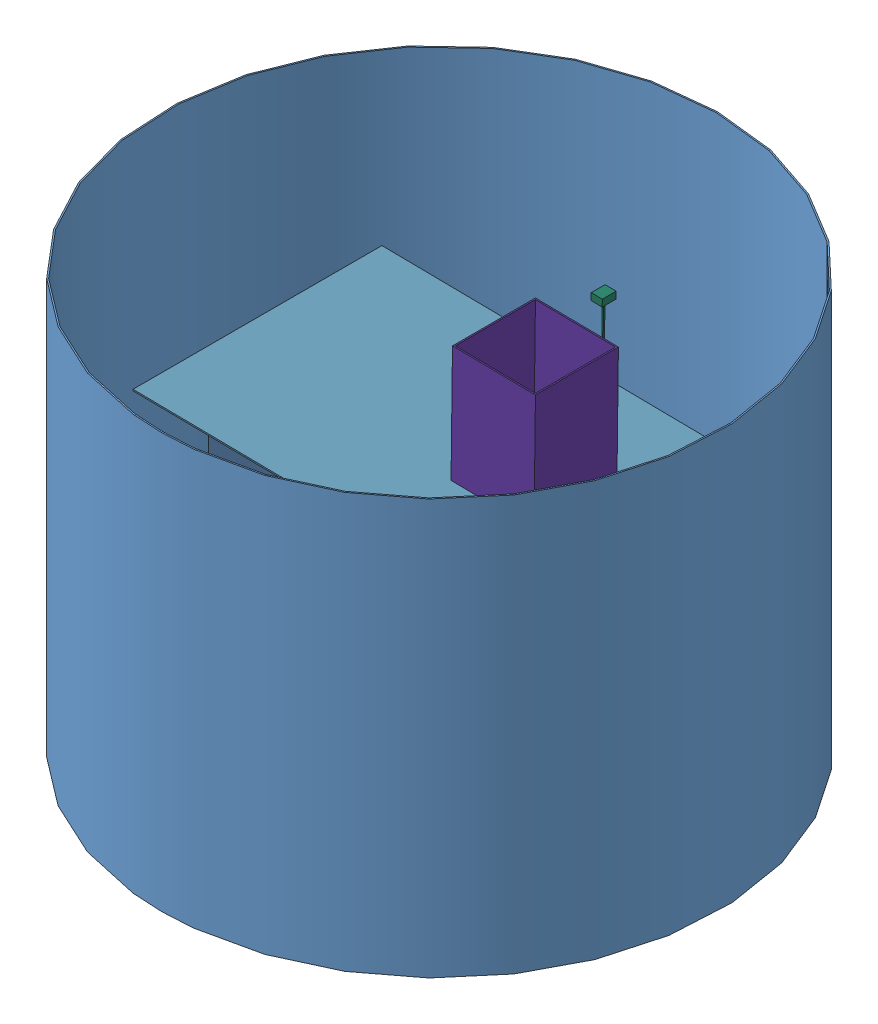
SolidWorks assembly Rover Lander assem, configuration Default. Lengths in mm.
Overall size (4020 3109.73 4020).
98 component instances, 37 part files, 5 mates.
Components (placement in the parent):
- lander_base_assem-1: lander_base_assem [Default] at (-53.6849 8.2156 22.7472) size (3202.83 1516.81 3190.9)
  - Lander base-1: Lander base [Default] at (714.6592 -461.0878 -63.8597) size (2500 70 1780)
  - leg_aluminum_rev-1: leg_aluminum_rev [Default] at (365.8635 -910.6524 482.3383) x (0 0.000985 1) z (-1 0 0) size (725.04 964.3 300)
    - base_leg-1: base_leg [Default] at (9.2435 -7.9699 0.537) size (300 140 300)
    - Main_leg-1: Main_leg [Default] at (-240.1972 521.872 0.537) x (0 0 -1) z (0.869495 0.493942 0) size (120 996.55 163.86)
    - Support_leg-1: Support_leg [Default] at (-74.206 133.9648 -89.463) x (0 0 -1) z (0.548366 0.836238 0) size (45 600 45)
    - leg_pin-1: leg_pin [Default] at (9.2435 82.777 -99.463) x (0 0 1) z (-0.667547 0.744568 0) size (200 20 20)
    - Support_leg-2: Support_leg [Default] at (-74.206 133.9648 90.537) x (0 0 -1) z (0.548366 0.836238 0) size (45 600 45)
    - leg_support_pin-1: leg_support_pin [Default] at (-40.7565 112.0301 -76.463) x (0 0 -1) z (1 0 0) size (26 10 10)
    - leg_support_pin-2: leg_support_pin [Default] at (-40.7565 112.0301 103.537) x (0 0 -1) z (1 0 0) size (26 10 10)
    - leg_joiner-1: leg_joiner [Default] at (-525.7944 410.0826 0.537) x (1 -0.000985 0) z (0 0 1) size (60 470.09 206)
    - leg_joiner_pin-1: leg_joiner_pin [Default] at (-525.3511 860.1724 -19.463) size (20 20 40)
  - leg_aluminum_rev-2: leg_aluminum_rev [Default] at (364.7896 -910.6524 -2390.0576) x (0 0.000985 -1) z (1 0 0) size (725.04 964.3 300)
    - base_leg-1: base_leg [Default] at (9.2435 -7.9699 0.537) size (300 140 300)
    - Main_leg-1: Main_leg [Default] at (-240.1972 521.872 0.537) x (0 0 -1) z (0.869495 0.493942 0) size (120 996.55 163.86)
    - Support_leg-1: Support_leg [Default] at (-74.206 133.9648 -89.463) x (0 0 -1) z (0.548366 0.836238 0) size (45 600 45)
    - leg_pin-1: leg_pin [Default] at (9.2435 82.777 -99.463) x (0 0 1) z (-0.667547 0.744568 0) size (200 20 20)
    - Support_leg-2: Support_leg [Default] at (-74.206 133.9648 90.537) x (0 0 -1) z (0.548366 0.836238 0) size (45 600 45)
    - leg_support_pin-1: leg_support_pin [Default] at (-40.7565 112.0301 -76.463) x (0 0 -1) z (1 0 0) size (26 10 10)
    - leg_support_pin-2: leg_support_pin [Default] at (-40.7565 112.0301 103.537) x (0 0 -1) z (1 0 0) size (26 10 10)
    - leg_joiner-1: leg_joiner [Default] at (-525.7944 410.0826 0.537) x (1 -0.000985 0) z (0 0 1) size (60 470.09 206)
    - leg_joiner_pin-1: leg_joiner_pin [Default] at (-525.3511 860.1724 -19.463) size (20 20 40)
  - leg_aluminum_rev-3: leg_aluminum_rev [Default] at (-1436.5452 -910.6524 -2390.0576) x (0 0.000985 -1) z (1 0 0) size (725.04 964.3 300)
    - base_leg-1: base_leg [Default] at (9.2435 -7.9699 0.537) size (300 140 300)
    - Main_leg-1: Main_leg [Default] at (-240.1972 521.872 0.537) x (0 0 -1) z (0.869495 0.493942 0) size (120 996.55 163.86)
    - Support_leg-1: Support_leg [Default] at (-74.206 133.9648 -89.463) x (0 0 -1) z (0.548366 0.836238 0) size (45 600 45)
    - leg_pin-1: leg_pin [Default] at (9.2435 82.777 -99.463) x (0 0 1) z (-0.667547 0.744568 0) size (200 20 20)
    - Support_leg-2: Support_leg [Default] at (-74.206 133.9648 90.537) x (0 0 -1) z (0.548366 0.836238 0) size (45 600 45)
    - leg_support_pin-1: leg_support_pin [Default] at (-40.7565 112.0301 -76.463) x (0 0 -1) z (1 0 0) size (26 10 10)
    - leg_support_pin-2: leg_support_pin [Default] at (-40.7565 112.0301 103.537) x (0 0 -1) z (1 0 0) size (26 10 10)
    - leg_joiner-1: leg_joiner [Default] at (-525.7944 410.0826 0.537) x (1 -0.000985 0) z (0 0 1) size (60 470.09 206)
    - leg_joiner_pin-1: leg_joiner_pin [Default] at (-525.3511 860.1724 -19.463) size (20 20 40)
  - leg_aluminum_rev-4: leg_aluminum_rev [Default] at (-1435.4713 -910.6524 482.3383) x (0 0.000985 1) z (-1 0 0) size (725.04 964.3 300)
    - base_leg-1: base_leg [Default] at (9.2435 -7.9699 0.537) size (300 140 300)
    - Main_leg-1: Main_leg [Default] at (-240.1972 521.872 0.537) x (0 0 -1) z (0.869495 0.493942 0) size (120 996.55 163.86)
    - Support_leg-1: Support_leg [Default] at (-74.206 133.9648 -89.463) x (0 0 -1) z (0.548366 0.836238 0) size (45 600 45)
    - leg_pin-1: leg_pin [Default] at (9.2435 82.777 -99.463) x (0 0 1) z (-0.667547 0.744568 0) size (200 20 20)
    - Support_leg-2: Support_leg [Default] at (-74.206 133.9648 90.537) x (0 0 -1) z (0.548366 0.836238 0) size (45 600 45)
    - leg_support_pin-1: leg_support_pin [Default] at (-40.7565 112.0301 -76.463) x (0 0 -1) z (1 0 0) size (26 10 10)
    - leg_support_pin-2: leg_support_pin [Default] at (-40.7565 112.0301 103.537) x (0 0 -1) z (1 0 0) size (26 10 10)
    - leg_joiner-1: leg_joiner [Default] at (-525.7944 410.0826 0.537) x (1 -0.000985 0) z (0 0 1) size (60 470.09 206)
    - leg_joiner_pin-1: leg_joiner_pin [Default] at (-525.3511 860.1724 -19.463) size (20 20 40)
  - MR_80b-1: MR_80b [Default] at (-1081.6322 -841.0878 -214.0715) size (153.97 380 153.97)
  - MR_80b-2: MR_80b [Default] at (16.7233 -838.4394 -1679.7382) x (0.999992 0 0.004071) z (-0.004071 0 0.999992) size (153.97 380 153.97)
  - Helium_tank-1: Helium_tank [Default] at (203.1711 -638.5192 -541.9795) x (0.94256 0.329358 0.055716) z (0.325345 -0.942975 0.070353) size (400 400 400)
  - Helium_tank-2: Helium_tank [Default] at (-953.3371 -635.4687 -1361.8199) x (0.977489 0.124684 0.170201) z (-0.107578 -0.399417 0.910436) size (400 400 400)
  - Hydrazine_tank-1: Hydrazine_tank [Default] at (-643.5463 -334.2768 -539.5578) x (0.363071 0.900077 0.240916) z (0.071543 0.230867 -0.970352) size (550 550 550)
  - Hydrazine_tank-2: Hydrazine_tank [Default] at (-75.2899 -529.4709 -1409.1331) x (0.901296 0.217178 -0.374832) z (0.418463 -0.660267 0.623647) size (550 550 550)
  - ramp-1: ramp [Default] at (-1794.7377 -454.508 -1543.8597) x (0.34202 -0.939693 0) z (0 0 1) size (1000 10 300)
  - ramp-2: ramp [Default] at (-1794.7377 -454.508 -63.8597) x (0.34202 -0.939693 0) z (0 0 1) size (1000 10 300)
  - ramp-3: ramp [Default] at (1066.0763 485.1846 -1543.8597) x (0.34202 0.939693 0) z (0 0 1) size (1000 10 300)
  - ramp-4: ramp [Default] at (1066.0763 485.1846 -63.8597) x (0.34202 0.939693 0) z (0 0 1) size (1000 10 300)
- layout_Assem_with_cover-1: layout_Assem_with_cover [Default] at (-567.9998 65.7276 -953.5275) x (0.999924 -0.012312 0) z (0 0 1) size (2907.8 2551.43 1996.55)
  - Rover_base-1: Rover_base [Default] at (-1064.6676 -0.8898 562.4151) size (2200 20 1100)
  - Neutron_spectrometer-1: Neutron_spectrometer [Default] at (-926.7762 19.1102 412.2415) size (300 57 300)
  - Neutron_spectrometer_electronics-1: Neutron_spectrometer_electronics [Default] at (-664.5809 19.1102 526.5713) size (180 30 130)
  - gc-1: gc [Default] at (-1085.6976 19.1102 139.436) size (100 80 100)
  - svr_box-1: svr_box [Default] at (435.3324 -172.8625 312.4151) size (600 2100 600)
  - xrf-1: xrf [Default] at (-1008.6936 19.1102 -66.8918) size (80 90 80)
  - geotechnical_exp-1: geotechnical_exp [Default] at (118.8439 19.1102 479.7148) x (0.999975 0 -0.007135) z (0.007135 0 0.999975) size (130 30 130)
  - penetrometer_3-1: penetrometer_3 [Default] at (989.1282 19.1102 -518.5473) x (-0.60186 0 0.798602) z (-0.798602 0 -0.60186) size (20 40 20)
  - penetrometer_3-2: penetrometer_3 [Default] at (934.1975 19.1102 -522.9905) size (20 40 20)
  - penetrometer_3-3: penetrometer_3 [Default] at (890.3988 19.1102 -523.0172) x (0.957231 0 -0.289323) z (0.289323 0 0.957231) size (20 40 20)
  - power-1: power [Default] at (-535.812 19.1102 343.3407) size (180 90 96)
  - geotechnical_exp_vane-1: geotechnical_exp_vane [Default] at (965.2252 19.1102 444.9326) size (220 40 220)
  - Magnents-1: Magnents [Default] at (-1020.4169 -10.8898 98.2252) size (45 10 45)
  - Becon-1: Becon [Default] at (656.9367 19.1102 515.9957) size (80 90 100)
  - Belly Cam-1: Belly Cam [Default] at (-660.0101 -90.1314 99.1462) size (150 100 150)
  - power_tank-1: power_tank [Default] at (-887.862 555.3324 -63.369) x (-0.812429 0.027314 0.58242) z (0.582091 -0.01957 0.812888) size (1560.46 846.95 1367.46)
    - power_tank_10-1: power_tank_10 [Default] at (-67.1815 281.3265 414.5148) size (500 500 500)
    - power_tank_10-2: power_tank_10 [Default] at (-251.8267 476.4977 723.0274) x (0.786037 -0.315714 0.53148) z (0.083274 0.905991 0.415025) size (500 500 500)
    - power_tank_10-3: power_tank_10 [Default] at (-733.4982 325.3571 380.2859) x (0.665484 -0.133715 0.734337) z (-0.678573 0.301428 0.669836) size (500 500 500)
    - power_tank_10-4: power_tank_10 [Default] at (-1034.3616 424.6302 664.9742) x (0.724325 0.588989 -0.358392) z (-0.233278 0.698521 0.676499) size (500 500 500)
    - power_tank_10-5: power_tank_10 [Default] at (-695.3433 297.5492 1147.5051) x (0.994968 0.097333 0.023775) z (-0.042044 0.190197 0.980845) size (500 500 500)
  - Tank_seperator_plate-1: Tank_seperator_plate [Default] at (435.3324 529.1102 512.4151) size (1500 10 1000)
  - power_tank-3: power_tank [Default] at (-887.862 502.888 93.4377) x (-0.812429 -0.027314 -0.58242) z (0.582091 0.01957 -0.812888) size (1560.46 846.95 1367.46)
    - power_tank_10-1: power_tank_10 [Default] at (-67.1815 281.3265 414.5148) size (500 500 500)
    - power_tank_10-2: power_tank_10 [Default] at (-251.8267 476.4977 723.0274) x (0.786037 -0.315714 0.53148) z (0.083274 0.905991 0.415025) size (500 500 500)
    - power_tank_10-3: power_tank_10 [Default] at (-733.4982 325.3571 380.2859) x (0.665484 -0.133715 0.734337) z (-0.678573 0.301428 0.669836) size (500 500 500)
    - power_tank_10-4: power_tank_10 [Default] at (-1034.3616 424.6302 664.9742) x (0.724325 0.588989 -0.358392) z (-0.233278 0.698521 0.676499) size (500 500 500)
    - power_tank_10-5: power_tank_10 [Default] at (-695.3433 297.5492 1147.5051) x (0.994968 0.097333 0.023775) z (-0.042044 0.190197 0.980845) size (500 500 500)
  - Rover_base_cover-1: Rover_base_cover [Default] at (1135.3324 1069.1102 -537.5849) x (1 0 0) z (0 0 -1) size (2200 1050 1100)
  - left_mobiiity_assemSLDASM-1: left_mobiiity_assemSLDASM [Default] at (483.248 -113.7012 -588.2789) x (-1 0 0) z (0 0 -1) size (2699.35 1341.14 400.39)
    - Suspension arms-1: Suspension arms [Default] at (-510.2208 -182.1885 -50.694) size (2035.36 1012.73 130)
    - wheel-1: wheel [Default] at (-515.577 -152.6706 299.306) x (-0.792605 -0.609735 0) z (0 0 -1) size (500 500 300.39)
    - wheel-2: wheel [Default] at (1479.7792 -157.1885 299.306) x (-0.72713 -0.6865 0) z (0 0 -1) size (500 500 300.39)
    - wheel-3: wheel [Default] at (499.7792 -157.1885 299.306) x (-0.949229 -0.314586 0) z (0 0 -1) size (500 500 300.39)
  - right_mobiiity_assemSLDASM-1: right_mobiiity_assemSLDASM [Default] at (657.788 -311.6325 815.2315) x (-1 0 0) z (0 0 -1) size (2495.36 1237.73 400.39)
    - Suspension arms_mirror-1: Suspension arms_mirror [Default] at (-335.6808 35.7938 152.8164) size (2035.36 1012.73 130)
    - wheel-1: wheel [Default] at (1654.3192 60.7938 -97.1836) size (500 500 300.39)
    - wheel-2: wheel [Default] at (-341.0371 65.3118 -97.1836) size (500 500 300.39)
    - wheel-3: wheel [Default] at (674.3192 60.7938 -97.1836) size (500 500 300.39)
  - solar cell-1: solar cell [Default] at (-1264.6676 1069.1102 -887.5849) x (-1 0 0) z (0 0 -1) size (2800 10 1800)
  - stero_imaging_sys-2: stero_imaging_sys [Default] at (325.3324 1059.1102 -537.5849) size (80 548.91 402.36)
  - arm-1: arm [Default] at (-1301.9354 19.1102 -517.5849) x (-1 0 0) z (0 0 -1) size (1100 100 100)
  - drill-1: drill [Default] at (-665.3253 539.1102 -237.5849) size (500 200 250)
  - scoop-1: scoop [Default] at (-1325.6367 25.0847 -517.5849) x (-0.755278 0.655405 0) z (0.655405 0.755278 0) size (211.36 101.82 100)
- shroud-1: shroud [Default] at (-514.7204 -910.2597 -953.5555) size (4020 3000 4020)
Mates (geometry in assembly coordinates):
- Tangent1: tangent anti-aligned: plane of lander_base_assem-1/Lander base-1 through (660.9743 -442.8722 -41.1125) normal (0 1 0); cylinder of layout_Assem_with_cover-1/left_mobiiity_assemSLDASM-1/wheel-2
- Tangent2: tangent anti-aligned: plane of lander_base_assem-1/Lander base-1 through (660.9743 -442.8722 -41.1125) normal (0 1 0); cylinder of layout_Assem_with_cover-1/right_mobiiity_assemSLDASM-1/wheel-2
- Coincident1: coincident aligned: plane of lander_base_assem-1/Lander base-1 through (660.9743 -442.8722 -41.1125) normal (0 0 1); plane of layout_Assem_with_cover-1/right_mobiiity_assemSLDASM-1/wheel-1 through (-1567.5438 -172.8227 -41.1125) normal (0 0 1)
- Distance2: distance = 200 mm: line of lander_base_assem-1/Lander base-1; plane of layout_Assem_with_cover-1/Rover_base_cover-1 through (-1632.3514 97.9447 -1491.1125) normal (-0.999924 0.012312 0)
- Tangent3: tangent: face of lander_base_assem-1/leg_aluminum_rev-1/base_leg-1; plane of shroud-1 through (-514.7204 -910.2597 -953.5555) normal (0 -1 0)
